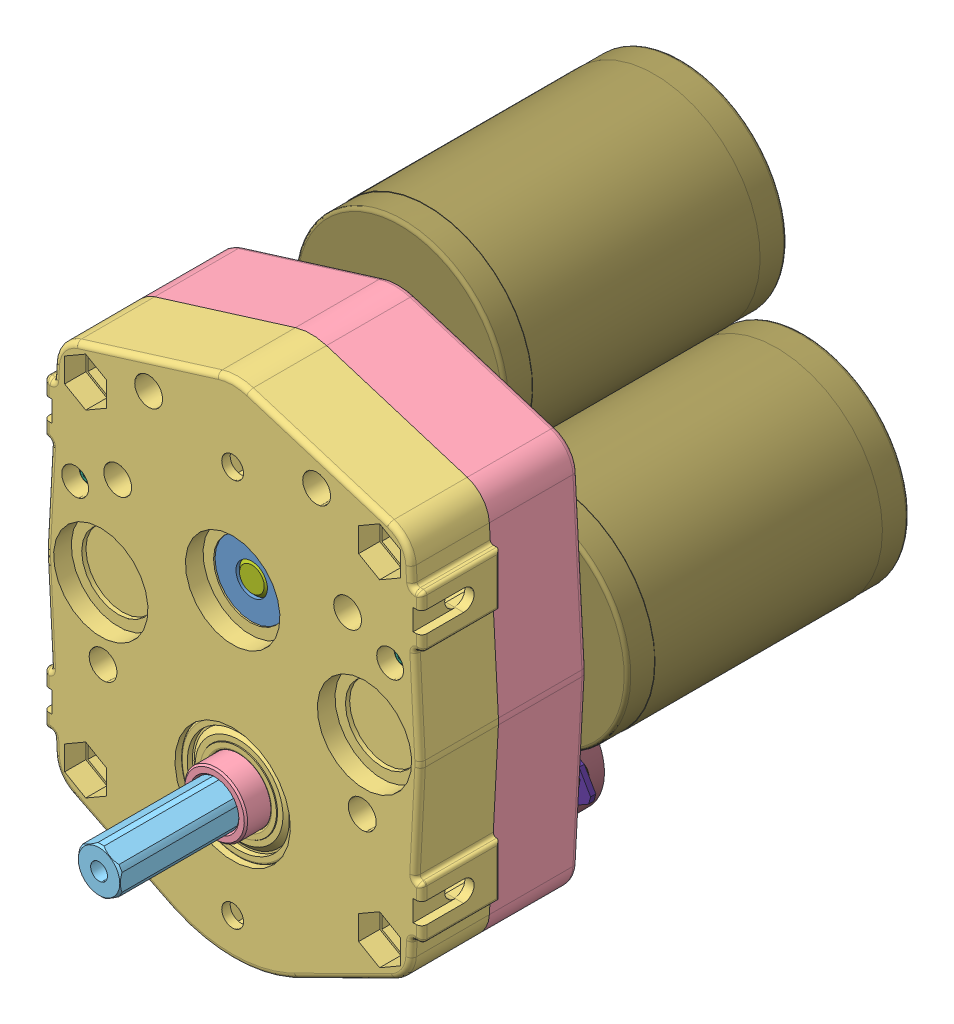
SolidWorks assembly 217-3195-STEP-20150102 Mini Cim, configuration Default. Lengths in mm.
Overall size (143.3 175.36 188.42).
77 component instances, 44 part files, 0 mates.
Components (placement in the parent):
- 217-2733-001 Rev2-1: 217-2733-001 Rev2 [Default] at (0 53.4162 37.6682) x (0 0 1) z (-0.00054 -1 0) size (7.11 24.61 24.61)
- 217-2733-001 Rev2-2: 217-2733-001 Rev2 [Default] at (0 53.4162 7.9248) x (0 0 -1) z (-0.038475 0.99926 0) size (7.11 24.61 24.61)
- 217-2731-001 Rev2-1: 217-2731-001 Rev2 [Default] at (0 0 0.0381) x (-0.099212 0.995066 0) z (0.995066 0.099212 0) size (31.12 7.94 31.12)
- 217-2789-001 Rev2-1: 217-2789-001 Rev2 [Default] at (0 0 43.2943) x (0 0 -1) z (-0.58471 0.811243 0) size (11.1 38.4 38.4)
- 217-2778-001 Rev2_NCQ8A075-050M-1: 217-2778-001 Rev2_NCQ8A075-050M [Default] at (0 0 -53.848) x (-0.707107 0.707107 0) z (0 0 1) size (31.75 33.34 39.88)
  - 217-2778-NCQ8A075-050M_NCQ8 Tube_075A-1: 217-2778-NCQ8A075-050M_NCQ8 Tube_075A [Default] at origin size (31.75 33.34 26.92)
  - 217-2778-NCQ8A075-050M_NCQ8 Rod_075M-1: 217-2778-NCQ8A075-050M_NCQ8 Rod_075M [Default] at (0 0 -8.85) x (0.866025 -0.5 0) z (0 0 1) size (18.95 18.95 35.27)
  - 217-2778-NCQ8A075-050M_Snap Ring_075-1: 217-2778-NCQ8A075-050M_Snap Ring_075 [Default] at (0 0 10.362) size (21 20.74 0.97)
- 217-2428-012 Rev2-1: 217-2428-012 Rev2 [Default] at (0 0 -40.386) size (63.5 22.23 2.29)
- 217-2428-005 Rev1-1: 217-2428-005 Rev1 [Default] at (25.4 0 -19.05) x (-0.557362 -0.83027 0) z (-0.83027 0.557362 0) size (7.33 38.98 6.35)
- 217-2428-005 Rev1-2: 217-2428-005 Rev1 [Default] at (-25.4 0 -19.05) x (0.667436 0.744667 0) z (0.744667 -0.667436 0) size (7.33 38.98 6.35)
- SCREW-832-0375-1: SCREW-832-0375 [Default] at (25.4 0 -42.5958) x (0 0 1) z (-0.875404 0.483392 0) size (11.73 7.92 7.92)
- SCREW-832-0375-2: SCREW-832-0375 [Default] at (-25.4 0 -42.5958) x (0 0 1) z (-0.966319 0.257347 0) size (11.73 7.92 7.92)
- SCREW-832-0375-3: SCREW-832-0375 [Default] at (25.4 0 5.3848) x (0 0 -1) z (1 0 0) size (11.73 7.92 7.92)
- SCREW-832-0375-4: SCREW-832-0375 [Default] at (-25.4 0 5.3848) x (0 0 -1) z (0.941463 -0.337115 0) size (11.73 7.92 7.92)
- SBS1_SBS-0632-0250-1: SBS1_SBS-0632-0250 [Default] at (15.494 0 -36.2458) x (0 0 -1) z (0.854303 -0.519775 0) size (8.57 6.68 6.65)
- SBS1_SBS-0632-0250-2: SBS1_SBS-0632-0250 [Default] at (-15.494 0 -36.2458) x (0 0 -1) z (0.854303 -0.519775 0) size (8.57 6.68 6.65)
- 217-4098-100 Rev1-1: 217-4098-100 Rev1 [Default] at (0 0 -16.927) x (-0.503316 0.864103 0) z (0 0 1) size (18.03 19.79 22.46)
  - 217-4098-006 Rev2-1: 217-4098-006 Rev2 [Default] at (0 0 -4.6312) x (0 -1 0) z (0 0 -1) size (18.09 11.02 22.46)
  - 217-4098-006 Rev2-2: 217-4098-006 Rev2 [Default] at (0 0 -4.6312) x (0 1 0) z (0 0 -1) size (18.09 11.02 22.46)
  - 217-3489-001 Rev1-1: 217-3489-001 Rev1 [Default] at (0 0 -4.6312) x (0 0 1) z (-0.980217 -0.197926 0) size (4.77 12.7 12.7)
  - 97633A130_97633A130_grv-1: 97633A130_97633A130_grv [Default] at (0 0 -7.33) x (0 0 -1) z (0.979861 0.199683 0) size (0.64 8.74 7.34)
  - 91251A107_91251A107-1: 91251A107_91251A107 [Default] at (-4.8375 -6.735 -9.4343) x (0 0.863883 -0.503692) z (-1 0 0) size (4.65 4.65 10.79)
  - 91251A107_91251A107-2: 91251A107_91251A107 [Default] at (4.8375 6.735 -9.4343) x (0 0.470889 -0.882193) z (1 0 0) size (4.65 4.65 10.79)
- 217-2428-017 Rev2-1: 217-2428-017 Rev2 [Default] at (12.7 -21.997 -3.614) x (-0.578458 -0.815712 0) z (0 0 -1) size (14.73 14.73 7.37)
- 217-2428-016 Rev3_Spur01-1: 217-2428-016 Rev3_Spur01 [Default] at (0 0 -3.614) x (0.873157 -0.48744 0) z (0 0 1) size (40.67 40.74 13.32)
- 217-2428-019 Rev1-1: 217-2428-019 Rev1 [Default] at (12.7 -21.997 -20.6248) x (0.866025 0.5 0) z (0 0 1) size (50.8 19.05 1.57)
- 217-2428-006 Rev1-1: 217-2428-006 Rev1 [Default] at (32.079 -14.2875 -9.525) x (-0.752416 0.658689 0) z (0.658689 0.752416 0) size (7.33 19.93 6.35)
- 217-2428-006 Rev1-2: 217-2428-006 Rev1 [Default] at (-3.6662 -34.925 -9.525) x (0.84498 0.534798 0) z (0.534798 -0.84498 0) size (7.33 19.93 6.35)
- SCREW-832-0375-5: SCREW-832-0375 [Default] at (32.079 -14.2875 4.7498) x (0 0 -1) z (0.980613 0.195955 0) size (11.73 7.92 7.92)
- SCREW-832-0375-6: SCREW-832-0375 [Default] at (-3.6662 -34.925 5.3848) x (0 0 -1) z (-0.672515 -0.740083 0) size (11.73 7.92 7.92)
- SCREW-832-0375-7: SCREW-832-0375 [Default] at (-3.6662 -34.925 -22.8346) x (0 0 1) z (0.948865 0.315681 0) size (11.73 7.92 7.92)
- SCREW-832-0375-8: SCREW-832-0375 [Default] at (32.079 -14.2875 -22.8346) x (0 0 1) z (-0.875404 0.483392 0) size (11.73 7.92 7.92)
- 217-2614-001_12t-1: 217-2614-001_12t [Default] at (36.9798 39.6868 15.8623) x (-0.087156 0.996195 0) z (0 0 1) size (18.29 18.29 19)
- 217-2761-001 rev1-1: 217-2761-001 rev1 [Default] at (33.1943 39.3556 16.1) x (0.087156 -0.996195 0) z (0 0 1) size (2 2 20)
- 217-2761-001 rev1-2: 217-2761-001 rev1 [Default] at (-40.7653 40.018 16.1) x (0.087156 0.996195 0) z (0 0 1) size (2 2 20)
- 217-2614-001_12t-2: 217-2614-001_12t [Default] at (-36.9798 39.6868 15.8623) x (0.087156 0.996195 0) z (0 0 1) size (18.29 18.29 19)
- 217-2614-001_12t-3: 217-2614-001_12t [Default] at (0 92.8624 15.8623) x (0.97459 0.223996 0) z (0 0 1) size (18.29 18.29 19)
- 217-2761-001 rev1-3: 217-2761-001 rev1 [Default] at (-0.8512 96.5658 16.1) x (0.97459 0.223996 0) z (0 0 1) size (2 2 20)
- 217-3195-002 rev2-1: 217-3195-002 rev2 [Default] at (0 0 50.546) x (-1 0 0) z (0 0 -1) size (114.31 152.24 24.96)
- 217-3195-001 Rev1-1: 217-3195-001 Rev1 [Default] at origin size (113.41 152.24 26.86)
- 276-1027-001-1: 276-1027-001 [Default] at (47.625 58.1787 6.35) x (0 1 0) z (-1 0 0) size (8.61 5.64 9.94)
- 276-1027-001-2: 276-1027-001 [Default] at (-47.625 58.1787 6.35) x (0 -1 0) z (1 0 0) size (8.61 5.64 9.94)
- SCREW-832-1750-1: SCREW-832-1750 [Default] at (-47.625 58.1787 47.0408) x (0 0 -1) z (-0.960822 -0.277167 0) size (46.66 7.92 7.92)
- SCREW-832-1750-2: SCREW-832-1750 [Default] at (47.625 58.1787 47.0408) x (0 0 -1) z (-0.960822 -0.277167 0) size (46.66 7.92 7.92)
- 217-2428-004 Rev3-1: 217-2428-004 Rev3 [Default] at (0 53.4162 22.7711) x (-0.709585 0.70462 0) z (0 0 1) size (11 9.53 43.92)
- 217-2428-021 Rev1-1: 217-2428-021 Rev1 [Default] at (0 53.4162 9.5123) x (0.451333 -0.892356 0) z (0 0 1) size (15.88 15.88 3.17)
- 217-2428-029 Rev1-1: 217-2428-029 Rev1 [Default] at (0 53.4162 36.957) x (0.999846 0.017557 0) z (0 0 1) size (15.88 15.88 1.12)
- Grayhill Lock Washer-1: Grayhill Lock Washer [Default] at (12.7 -21.997 -18.6817) x (0.467173 -0.884166 0) z (0 0 1) size (19.69 19.69 0.74)
- Grayhill Nut-1: Grayhill Nut [Default] at (12.7 -21.997 -17.0434) x (0.984088 0.177684 0) z (0 0 1) size (18.33 15.88 2.54)
- MiniCIM_Motor-3: MiniCIM_Motor [Default] at (0 92.8624 0) x (0 0 -1) z (0.223996 -0.97459 0) size (133.06 64.01 64.01)
- MiniCIM_Motor-2: MiniCIM_Motor [Default] at (-36.9798 39.6868 0) x (0 0 -1) z (0.996195 -0.087156 0) size (133.06 64.01 64.01)
- MiniCIM_Motor-4: MiniCIM_Motor [Default] at (36.9798 39.6868 0) x (0 0 -1) z (0.996195 0.087156 0) size (133.06 64.01 64.01)
- Grahill Encoder-1: Grahill Encoder [Default] at (12.7 -21.997 -16.1798) x (-0.580071 0.814566 0) z (-0.814566 -0.580071 0) size (31.75 31.12 31.75)
- 217-3210-001 Rev1_30t-1: 217-3210-001 Rev1_30t [Default] at (0 53.4162 30.0736) x (-0.966828 0.255427 0) z (0 0 1) size (41.01 41.12 12.65)
- 217-3291-001 Rev3-1: 217-3291-001 Rev3 [Default] at (0 0 0.0889) size (74.97 75.02 117.22)
  - 217-2428-008 Rev2-1: 217-2428-008 Rev2 [Default] at (0 0 10.2679) size (31.75 31.75 1.59)
  - 217-2428-028 Rev1_97633A250-1: 217-2428-028 Rev1_97633A250 [Default] at (0 0 37.1221) x (0 0 1) z (0.9357 -0.352797 0) size (1.07 23.39 21.18)
  - 217-2428-007 Rev1-1: 217-2428-007 Rev1 [Default] at (4.5085 7.809 14.2494) x (0.57515 -0.320306 -0.752732) z (-0.697826 0.288078 -0.655782) size (6.35 6.35 6.35)
  - 217-2428-007 Rev1-2: 217-2428-007 Rev1 [Default] at (3.1375 5.4343 26.9494) x (0.444163 0.822893 0.354354) z (0.803342 -0.540896 0.249144) size (6.35 6.35 6.35)
  - 217-3212-101 Rev1-1: 217-3212-101 Rev1 [Default] at (-7.461 13.6656 45.3224) x (0.998507 0.054615 0) z (0 0 -1) size (46.46 46.56 12.7)
    - 217-2428-022 Rev1-1: 217-2428-022 Rev1 [Default] at (6.7035 14.0527 24.6087) size (28.57 28.57 6.1)
    - 217-3212-001 Rev1_34t-1: 217-3212-001 Rev1_34t [Default] at (6.7035 14.0527 27.9107) size (46.46 46.56 11.11)
  - 217-3222-101 Rev1-1: 217-3222-101 Rev1 [Default] at (-16.5535 14.1005 52.7371) x (0.999887 0.015021 0) z (0 0 -1) size (73.87 73.92 12.7)
    - 217-2428-022 Rev1-1: 217-2428-022 Rev1 [Default] at (16.3398 14.3476 19.3234) size (28.57 28.57 6.1)
    - 217-3222-001 Rev1_Spur01-1: 217-3222-001 Rev1_Spur01 [Default] at (16.3398 14.3476 22.6254) x (0.999377 0.0353 0) z (0 0 1) size (71.39 71.45 11.11)
  - 217-4098-000 Rev2-1: 217-4098-000 Rev2 [Default] x (0 1 0) z (0 0 1) size (22.23 22.23 117.22)
    - 217-4098-005 Rev1_91612A226-1: 217-4098-005 Rev1_91612A226 [Default] at (0 0 46.2661) x (-0.144757 0 0.989467) z (0 -1 0) size (3.02 3.15 18.22)
    - 217-4098-003 Rev2-1: 217-4098-003 Rev2 [Default] x (1 0 0) z (0 0 -1) size (22.23 22.23 55.94)
    - 217-4098-002 Rev3-1: 217-4098-002 Rev3 [Default] at (0 0 62.9285) x (0 0 1) z (-1 0 0) size (59.88 12.73 14.67)
    - 217-4098-004 Rev1-1: 217-4098-004 Rev1 [Default] at (0 0 14.2494) x (-0.610335 0.792144 0) z (0 0 1) size (11.68 11.68 56)
  - 217-2428-007 Rev1-3: 217-2428-007 Rev1 [Default] at (4.355 -6.8759 14.2494) x (-0.564969 -0.337942 -0.752732) z (0.598396 0.460296 -0.655782) size (6.35 6.35 6.35)
  - 217-2428-007 Rev1-4: 217-2428-007 Rev1 [Default] at (-8.2857 0.5994 14.2494) x (-0.010182 0.658248 -0.752732) z (0.09943 -0.748374 -0.655782) size (6.35 6.35 6.35)
  - 217-2428-007 Rev1-5: 217-2428-007 Rev1 [Default] at (2.984 -4.5013 26.9494) x (0.490565 -0.796103 0.354354) z (-0.870101 -0.425267 0.249144) size (6.35 6.35 6.35)
  - 217-2428-007 Rev1-6: 217-2428-007 Rev1 [Default] at (-5.5437 0.5994 26.9494) x (-0.934728 -0.02679 0.354354) z (0.066759 0.966163 0.249144) size (6.35 6.35 6.35)
- 217-2711-002 Rev1_50t-1: 217-2711-002 Rev1_50t [Default] at (0 53.4162 17.4244) x (0.262208 -0.965011 0) z (0 0 1) size (66.7 66.76 12.65)
- 217-2428-023 Rev1_9714K3-1: 217-2428-023 Rev1_9714K3 [Default] at (0 0 37.7444) x (-0.089015 0.99603 0) z (0.99603 0.089015 0) size (26.82 4.09 28.39)
